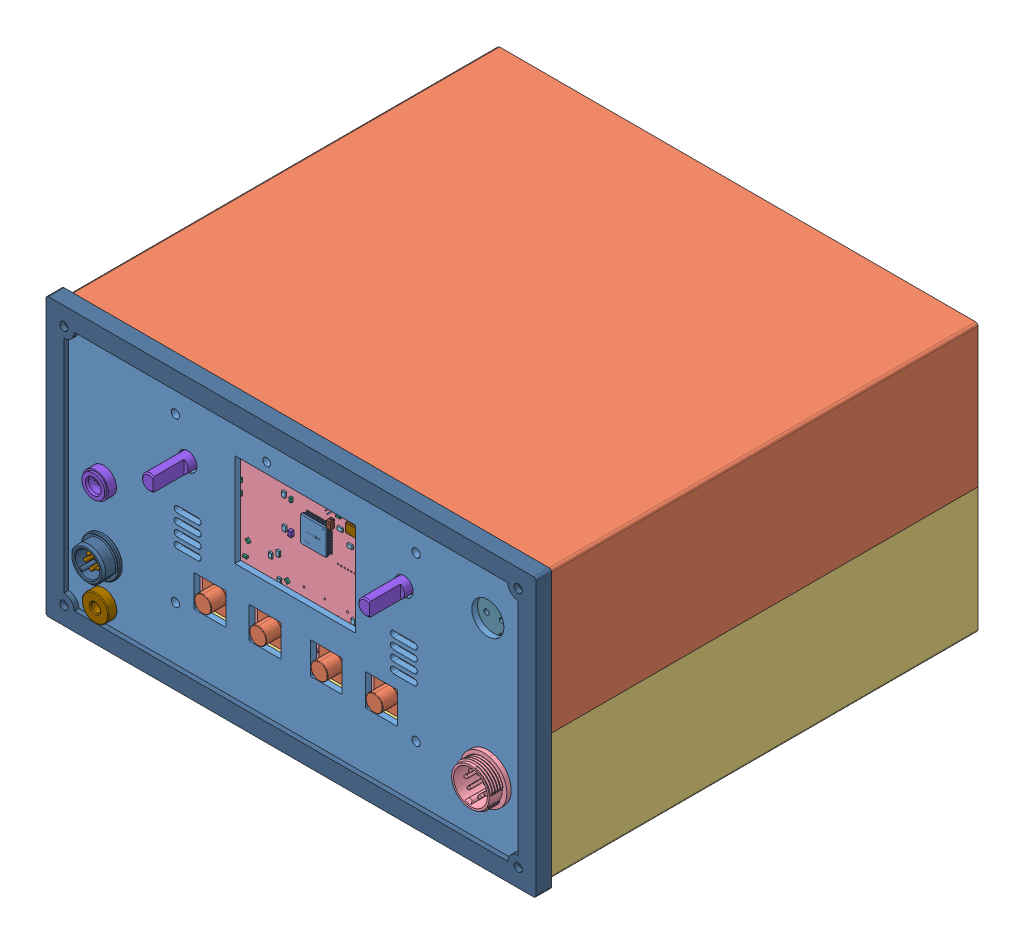
SolidWorks assembly ASM, configuration По умолчанию. Lengths in mm.
Overall size (188.8 107.81 193.5).
328 component instances, 46 part files, 35 mates.
Components (placement in the parent):
- part_1-1: part_1 [По умолчанию] at (42.0836 76.5265 112.7484) size (180 98 2.2)
- part_3-1: part_3 [По умолчанию] at (182.1946 155.2265 -55.2516) x (-1 0 0) z (0 0 1) size (185.2 54.6 170)
- part_4-1: part_4 [По умолчанию] at (182.1946 56.8265 114.7484) x (-1 0 0) z (0 0 -1) size (185.2 51.6 170)
- gx16-8-1: gx16-8 [По умолчанию] at (165.9946 82.0265 105.3984) x (0.970583 -0.240767 0) z (-0.240767 -0.970583 0) size (18 20.75 18)
- 3D_PCB_Soldering_station_p1.step-1: 3D_PCB_Soldering_station_p1.step [По умолчанию] at (42.0834 76.5267 105.1483) x (1 -0.000002 0) z (0 0 1) size (108.62 71.4 34.5)
  - DLKy-R302-R0805.step-1: DLKy-R302-R0805.step [По умолчанию] at (43.1801 57.1501 1.6) x (-1 0 0) z (0 0 1) size (2 1.3 0.61)
    - COMPOUND.step-1: COMPOUND.step [По умолчанию] at origin size (2 1.3 0.61)
  - DLKy-R303-R0805.step-1: DLKy-R303-R0805.step [По умолчанию] at (37.4651 52.7051 1.6) x (0 1 0) z (0 0 1) size (2 1.3 0.61)
    - COMPOUND.step-1: COMPOUND.step [По умолчанию] at origin size (2 1.3 0.61)
  - DLKy-R314-R0805.step-1: DLKy-R314-R0805.step [По умолчанию] at (32.3851 29.8451 1.6) x (0 1 0) z (0 0 1) size (2 1.3 0.61)
    - COMPOUND.step-1: COMPOUND.step [По умолчанию] at origin size (2 1.3 0.61)
  - DLKy-R315-R0805.step-1: DLKy-R315-R0805.step [По умолчанию] at (35.3061 31.8771 1.6) x (0 1 0) z (0 0 1) size (2 1.3 0.61)
    - COMPOUND.step-1: COMPOUND.step [По умолчанию] at origin size (2 1.3 0.61)
  - DLKy-R202-R0805.step-1: DLKy-R202-R0805.step [По умолчанию] at (62.9921 48.1331 1.6) x (-1 0 0) z (0 0 1) size (2 1.3 0.61)
    - COMPOUND.step-1: COMPOUND.step [По умолчанию] at origin size (2 1.3 0.61)
  - DLKy-R203-R0805.step-1: DLKy-R203-R0805.step [По умолчанию] at (37.7191 41.5291 1.6) x (0 1 0) z (0 0 1) size (2 1.3 0.61)
    - COMPOUND.step-1: COMPOUND.step [По умолчанию] at origin size (2 1.3 0.61)
  - DLKy-R204-R0805.step-1: DLKy-R204-R0805.step [По умолчанию] at (55.4991 61.0871 1.6) x (0 -1 0) z (0 0 1) size (2 1.3 0.61)
    - COMPOUND.step-1: COMPOUND.step [По умолчанию] at origin size (2 1.3 0.61)
  - DLKy-R501-R0805.step-1: DLKy-R501-R0805.step [По умолчанию] at (85.4712 23.622 1.6) x (0 -1 0) z (0 0 1) size (2 1.3 0.61)
    - COMPOUND.step-1: COMPOUND.step [По умолчанию] at origin size (2 1.3 0.61)
  - DLKy-R502-R0805.step-1: DLKy-R502-R0805.step [По умолчанию] at (90.5512 2.54 1.6) x (0 -1 0) z (0 0 1) size (2 1.3 0.61)
    - COMPOUND.step-1: COMPOUND.step [По умолчанию] at origin size (2 1.3 0.61)
  - DLKy-R503-R0805.step-1: DLKy-R503-R0805.step [По умолчанию] at (64.2621 23.622 1.6) x (0 -1 0) z (0 0 1) size (2 1.3 0.61)
    - COMPOUND.step-1: COMPOUND.step [По умолчанию] at origin size (2 1.3 0.61)
  - DLKy-R504-R0805.step-1: DLKy-R504-R0805.step [По умолчанию] at (69.3421 2.54 1.6) x (0 -1 0) z (0 0 1) size (2 1.3 0.61)
    - COMPOUND.step-1: COMPOUND.step [По умолчанию] at origin size (2 1.3 0.61)
  - DLKy-R505-R0805.step-1: DLKy-R505-R0805.step [По умолчанию] at (35.6871 22.987 1.6) x (0 -1 0) z (0 0 1) size (2 1.3 0.61)
    - COMPOUND.step-1: COMPOUND.step [По умолчанию] at origin size (2 1.3 0.61)
  - DLKy-R506-R0805.step-1: DLKy-R506-R0805.step [По умолчанию] at (30.4801 2.54 1.6) x (0 -1 0) z (0 0 1) size (2 1.3 0.61)
    - COMPOUND.step-1: COMPOUND.step [По умолчанию] at origin size (2 1.3 0.61)
  - DLKy-R507-R0805.step-1: DLKy-R507-R0805.step [По умолчанию] at (19.431 23.622 1.6) x (0 -1 0) z (0 0 1) size (2 1.3 0.61)
    - COMPOUND.step-1: COMPOUND.step [По умолчанию] at origin size (2 1.3 0.61)
  - DLKy-R508-R0805.step-1: DLKy-R508-R0805.step [По умолчанию] at (24.511 2.54 1.6) x (0 -1 0) z (0 0 1) size (2 1.3 0.61)
    - COMPOUND.step-1: COMPOUND.step [По умолчанию] at origin size (2 1.3 0.61)
  - DLKy-R509-R0805.step-1: DLKy-R509-R0805.step [По умолчанию] at (17.272 45.5931 1.6) x (-1 0 0) z (0 0 1) size (2 1.3 0.61)
    - COMPOUND.step-1: COMPOUND.step [По умолчанию] at origin size (2 1.3 0.61)
  - DLKy-R510-R0805.step-1: DLKy-R510-R0805.step [По умолчанию] at (17.272 48.2601 1.6) x (-1 0 0) z (0 0 1) size (2 1.3 0.61)
    - COMPOUND.step-1: COMPOUND.step [По умолчанию] at origin size (2 1.3 0.61)
  - DLKy-R514-R0805.step-1: DLKy-R514-R0805.step [По умолчанию] at (15.367 41.9101 1.6) size (2 1.3 0.61)
    - COMPOUND.step-1: COMPOUND.step [По умолчанию] at origin size (2 1.3 0.61)
  - DLKy-R515-R0805.step-1: DLKy-R515-R0805.step [По умолчанию] at (82.2962 48.1331 1.6) size (2 1.3 0.61)
    - COMPOUND.step-1: COMPOUND.step [По умолчанию] at origin size (2 1.3 0.61)
  - DLKy-R516-R0805.step-1: DLKy-R516-R0805.step [По умолчанию] at (82.2962 45.5931 1.6) size (2 1.3 0.61)
    - COMPOUND.step-1: COMPOUND.step [По умолчанию] at origin size (2 1.3 0.61)
  - DLKy-R520-R0805.step-1: DLKy-R520-R0805.step [По умолчанию] at (82.6772 37.9731 1.6) x (-1 0 0) z (0 0 1) size (2 1.3 0.61)
    - COMPOUND.step-1: COMPOUND.step [По умолчанию] at origin size (2 1.3 0.61)
  - DLKy-R522-R0805.step-1: DLKy-R522-R0805.step [По умолчанию] at (67.9451 49.1491 1.6) size (2 1.3 0.61)
    - COMPOUND.step-1: COMPOUND.step [По умолчанию] at origin size (2 1.3 0.61)
  - DLKy-R523-R0805.step-1: DLKy-R523-R0805.step [По умолчанию] at (59.1821 51.9431 1.6) x (-1 0 0) z (0 0 1) size (2 1.3 0.61)
    - COMPOUND.step-1: COMPOUND.step [По умолчанию] at origin size (2 1.3 0.61)
  - DLKy-R601-R0805.step-1: DLKy-R601-R0805.step [По умолчанию] at (11.811 23.368 1.6) x (0 -1 0) z (0 0 1) size (2 1.3 0.61)
    - COMPOUND.step-1: COMPOUND.step [По умолчанию] at origin size (2 1.3 0.61)
  - DLKy-R602-R0805.step-1: DLKy-R602-R0805.step [По умолчанию] at (14.097 23.368 1.6) x (0 1 0) z (0 0 1) size (2 1.3 0.61)
    - COMPOUND.step-1: COMPOUND.step [По умолчанию] at origin size (2 1.3 0.61)
  - DLKy-R308-R0805.step-1: DLKy-R308-R0805.step [По умолчанию] at (17.526 57.4041 0) x (-1 0 0) z (0 0 -1) size (2 1.3 0.61)
    - COMPOUND.step-1: COMPOUND.step [По умолчанию] at origin size (2 1.3 0.61)
  - DLKy-R313-R0805.step-1: DLKy-R313-R0805.step [По умолчанию] at (27.9401 65.4051 0) x (0 1 0) z (0 0 -1) size (2 1.3 0.61)
    - COMPOUND.step-1: COMPOUND.step [По умолчанию] at origin size (2 1.3 0.61)
  - DLKy-R305-R0805.step-1: DLKy-R305-R0805.step [По умолчанию] at (36.4491 50.1651 0) x (1 0 0) z (0 0 -1) size (2 1.3 0.61)
    - COMPOUND.step-1: COMPOUND.step [По умолчанию] at origin size (2 1.3 0.61)
  - DLKy-R306-R0805.step-1: DLKy-R306-R0805.step [По умолчанию] at (32.3851 50.1651 0) x (1 0 0) z (0 0 -1) size (2 1.3 0.61)
    - COMPOUND.step-1: COMPOUND.step [По умолчанию] at origin size (2 1.3 0.61)
  - DLKy-R310-R0805.step-1: DLKy-R310-R0805.step [По умолчанию] at (35.8141 62.1031 0) x (1 0 0) z (0 0 -1) size (2 1.3 0.61)
    - COMPOUND.step-1: COMPOUND.step [По умолчанию] at origin size (2 1.3 0.61)
  - DLKy-R311-R0805.step-1: DLKy-R311-R0805.step [По умолчанию] at (32.2581 63.1191 0) x (0 -1 0) z (0 0 -1) size (2 1.3 0.61)
    - COMPOUND.step-1: COMPOUND.step [По умолчанию] at origin size (2 1.3 0.61)
  - DLKy-R407-R0805.step-1: DLKy-R407-R0805.step [По умолчанию] at (20.955 32.3851 0) x (-0.707107 0.707107 0) z (0 0 -1) size (2 1.3 0.61)
    - COMPOUND.step-1: COMPOUND.step [По умолчанию] at origin size (2 1.3 0.61)
  - DLKy-R304-R0805.step-1: DLKy-R304-R0805.step [По умолчанию] at (39.6241 54.6101 0) x (1 0 0) z (0 0 -1) size (2 1.3 0.61)
    - COMPOUND.step-1: COMPOUND.step [По умолчанию] at origin size (2 1.3 0.61)
  - DLKy-R309-R0805.step-1: DLKy-R309-R0805.step [По умолчанию] at (39.6241 57.0231 0) x (1 0 0) z (0 0 -1) size (2 1.3 0.61)
    - COMPOUND.step-1: COMPOUND.step [По умолчанию] at origin size (2 1.3 0.61)
  - DLKy-R521-R0805.step-1: DLKy-R521-R0805.step [По умолчанию] at (82.6772 36.7031 0) x (-1 0 0) z (0 0 -1) size (2 1.3 0.61)
    - COMPOUND.step-1: COMPOUND.step [По умолчанию] at origin size (2 1.3 0.61)
  - DLKy-R408-R0805.step-1: DLKy-R408-R0805.step [По умолчанию] at (17.907 35.4331 0) x (-0.707107 0.707107 0) z (0 0 -1) size (2 1.3 0.61)
    - COMPOUND.step-1: COMPOUND.step [По умолчанию] at origin size (2 1.3 0.61)
  - DLKy-R409-R0805.step-1: DLKy-R409-R0805.step [По умолчанию] at (74.9301 32.0041 0) x (-1 0 0) z (0 0 -1) size (2 1.3 0.61)
    - COMPOUND.step-1: COMPOUND.step [По умолчанию] at origin size (2 1.3 0.61)
  - DLKy-R410-R0805.step-1: DLKy-R410-R0805.step [По умолчанию] at (77.4702 28.4481 0) x (0 -1 0) z (0 0 -1) size (2 1.3 0.61)
    - COMPOUND.step-1: COMPOUND.step [По умолчанию] at origin size (2 1.3 0.61)
  - DLKy-R411-R0805.step-1: DLKy-R411-R0805.step [По умолчанию] at (80.3912 28.4481 0) x (0 1 0) z (0 0 -1) size (2 1.3 0.61)
    - COMPOUND.step-1: COMPOUND.step [По умолчанию] at origin size (2 1.3 0.61)
  - DLKy-R412-R0805.step-1: DLKy-R412-R0805.step [По умолчанию] at (84.9632 28.4481 0) x (0 1 0) z (0 0 -1) size (2 1.3 0.61)
    - COMPOUND.step-1: COMPOUND.step [По умолчанию] at origin size (2 1.3 0.61)
  - DLKy-R413-R0805.step-1: DLKy-R413-R0805.step [По умолчанию] at (63.7541 32.0041 0) x (-1 0 0) z (0 0 -1) size (2 1.3 0.61)
    - COMPOUND.step-1: COMPOUND.step [По умолчанию] at origin size (2 1.3 0.61)
  - DLKy-R414-R0805.step-1: DLKy-R414-R0805.step [По умолчанию] at (66.2941 28.4481 0) x (0 -1 0) z (0 0 -1) size (2 1.3 0.61)
    - COMPOUND.step-1: COMPOUND.step [По умолчанию] at origin size (2 1.3 0.61)
  - DLKy-R415-R0805.step-1: DLKy-R415-R0805.step [По умолчанию] at (69.2151 28.4481 0) x (0 1 0) z (0 0 -1) size (2 1.3 0.61)
    - COMPOUND.step-1: COMPOUND.step [По умолчанию] at origin size (2 1.3 0.61)
  - DLKy-R416-R0805.step-1: DLKy-R416-R0805.step [По умолчанию] at (73.7871 28.4481 0) x (0 1 0) z (0 0 -1) size (2 1.3 0.61)
    - COMPOUND.step-1: COMPOUND.step [По умолчанию] at origin size (2 1.3 0.61)
  - DLKy-R603-R0805.step-1: DLKy-R603-R0805.step [По умолчанию] at (45.9741 58.2931 0) x (0 1 0) z (0 0 -1) size (2 1.3 0.61)
    - COMPOUND.step-1: COMPOUND.step [По умолчанию] at origin size (2 1.3 0.61)
  - DLKy-R604-R0805.step-1: DLKy-R604-R0805.step [По умолчанию] at (46.9901 61.8491 0) x (1 0 0) z (0 0 -1) size (2 1.3 0.61)
    - COMPOUND.step-1: COMPOUND.step [По умолчанию] at origin size (2 1.3 0.61)
  - DLKy-L201-R0805.step-1: DLKy-L201-R0805.step [По умолчанию] at (44.0691 49.0221 0) x (0 1 0) z (0 0 -1) size (2 1.3 0.61)
    - COMPOUND.step-1: COMPOUND.step [По умолчанию] at origin size (2 1.3 0.61)
  - DLKy-R401-R0805.step-1: DLKy-R401-R0805.step [По умолчанию] at (25.9081 35.9411 0) x (0 1 0) z (0 0 -1) size (2 1.3 0.61)
    - COMPOUND.step-1: COMPOUND.step [По умолчанию] at origin size (2 1.3 0.61)
  - DLKy-R402-R0805.step-1: DLKy-R402-R0805.step [По умолчанию] at (28.7021 35.9411 0) x (0 1 0) z (0 0 -1) size (2 1.3 0.61)
    - COMPOUND.step-1: COMPOUND.step [По умолчанию] at origin size (2 1.3 0.61)
  - DLKy-R403-R0805.step-1: DLKy-R403-R0805.step [По умолчанию] at (23.749 28.8291 0) x (0 1 0) z (0 0 -1) size (2 1.3 0.61)
    - COMPOUND.step-1: COMPOUND.step [По умолчанию] at origin size (2 1.3 0.61)
  - DLKy-R404-R0805.step-1: DLKy-R404-R0805.step [По умолчанию] at (33.5281 28.8291 0) x (0 1 0) z (0 0 -1) size (2 1.3 0.61)
    - COMPOUND.step-1: COMPOUND.step [По умолчанию] at origin size (2 1.3 0.61)
  - DLKy-R405-R0805.step-1: DLKy-R405-R0805.step [По умолчанию] at (27.3051 27.8131 0) x (-1 0 0) z (0 0 -1) size (2 1.3 0.61)
    - COMPOUND.step-1: COMPOUND.step [По умолчанию] at origin size (2 1.3 0.61)
  - DLKy-R406-R0805.step-1: DLKy-R406-R0805.step [По умолчанию] at (37.0841 27.8131 0) x (-1 0 0) z (0 0 -1) size (2 1.3 0.61)
    - COMPOUND.step-1: COMPOUND.step [По умолчанию] at origin size (2 1.3 0.61)
  - DLKy-R517-R0805.step-1: DLKy-R517-R0805.step [По умолчанию] at (89.0272 49.7841 0) x (0 1 0) z (0 0 -1) size (2 1.3 0.61)
    - COMPOUND.step-1: COMPOUND.step [По умолчанию] at origin size (2 1.3 0.61)
  - DLKy-R518-R0805.step-1: DLKy-R518-R0805.step [По умолчанию] at (94.1072 49.7841 0) x (0 1 0) z (0 0 -1) size (2 1.3 0.61)
    - COMPOUND.step-1: COMPOUND.step [По умолчанию] at origin size (2 1.3 0.61)
  - DLKy-R519-R0805.step-1: DLKy-R519-R0805.step [По умолчанию] at (89.0272 56.5151 0) x (0 -1 0) z (0 0 -1) size (2 1.3 0.61)
    - COMPOUND.step-1: COMPOUND.step [По умолчанию] at origin size (2 1.3 0.61)
  - DLKy-R511-R0805.step-1: DLKy-R511-R0805.step [По умолчанию] at (5.715 49.2761 0) x (0 1 0) z (0 0 -1) size (2 1.3 0.61)
    - COMPOUND.step-1: COMPOUND.step [По умолчанию] at origin size (2 1.3 0.61)
  - DLKy-R512-R0805.step-1: DLKy-R512-R0805.step [По умолчанию] at (10.795 49.2761 0) x (0 1 0) z (0 0 -1) size (2 1.3 0.61)
    - COMPOUND.step-1: COMPOUND.step [По умолчанию] at origin size (2 1.3 0.61)
  - DLKy-R513-R0805.step-1: DLKy-R513-R0805.step [По умолчанию] at (5.715 56.2611 0) x (0 -1 0) z (0 0 -1) size (2 1.3 0.61)
    - COMPOUND.step-1: COMPOUND.step [По умолчанию] at origin size (2 1.3 0.61)
  - DLKy-R201-R0805.step-1: DLKy-R201-R0805.step [По умолчанию] at (52.9591 64.3891 0) x (1 0 0) z (0 0 -1) size (2 1.3 0.61)
    - COMPOUND.step-1: COMPOUND.step [По умолчанию] at origin size (2 1.3 0.61)
  - DLKy-R307-R0805.step-1: DLKy-R307-R0805.step [По умолчанию] at (20.066 54.7371 0) x (1 0 0) z (0 0 -1) size (2 1.3 0.61)
    - COMPOUND.step-1: COMPOUND.step [По умолчанию] at origin size (2 1.3 0.61)
  - DLKy-L101-R0805.step-1: DLKy-L101-R0805.step [По умолчанию] at (43.0531 35.3061 0) x (-1 0 0) z (0 0 -1) size (2 1.3 0.61)
    - COMPOUND.step-1: COMPOUND.step [По умолчанию] at origin size (2 1.3 0.61)
  - DLKy-L102-R0805.step-1: DLKy-L102-R0805.step [По умолчанию] at (39.4971 44.9581 0) x (1 0 0) z (0 0 -1) size (2 1.3 0.61)
    - COMPOUND.step-1: COMPOUND.step [По умолчанию] at origin size (2 1.3 0.61)
  - DLKy-R312-R0805.step-1: DLKy-R312-R0805.step [По умолчанию] at (27.9401 60.5791 0) x (0 -1 0) z (0 0 -1) size (2 1.3 0.61)
    - COMPOUND.step-1: COMPOUND.step [По умолчанию] at origin size (2 1.3 0.61)
  - DLKy-R301-R0805.step-1: DLKy-R301-R0805.step [По умолчанию] at (40.3861 61.4681 1.6) x (0 -1 0) z (0 0 1) size (2 1.3 0.61)
    - COMPOUND.step-1: COMPOUND.step [По умолчанию] at origin size (2 1.3 0.61)
  - DLKy-Q3-TO-252-3_L6.5-W5.8-P4.58-TL.step-1: DLKy-Q3-TO-252-3_L6.5-W5.8-P4.58-TL.step [По умолчанию] at (35.8141 20.955 0) x (0 -1 0) z (0 0 -1) size (9.47 6.6 2.3)
    - COMPOUND-0.step-1: COMPOUND-0.step [По умолчанию] at origin size (9.47 6.6 2.3)
  - DLKy-Q5-TO-252-3_L6.5-W5.8-P4.58-TL.step-1: DLKy-Q5-TO-252-3_L6.5-W5.8-P4.58-TL.step [По умолчанию] at (82.6772 20.955 0) x (0 -1 0) z (0 0 -1) size (9.47 6.6 2.3)
    - COMPOUND-0.step-1: COMPOUND-0.step [По умолчанию] at origin size (9.47 6.6 2.3)
  - DLKy-Q7-TO-252-3_L6.5-W5.8-P4.58-TL.step-1: DLKy-Q7-TO-252-3_L6.5-W5.8-P4.58-TL.step [По умолчанию] at (71.5011 20.955 0) x (0 -1 0) z (0 0 -1) size (9.47 6.6 2.3)
    - COMPOUND-0.step-1: COMPOUND-0.step [По умолчанию] at origin size (9.47 6.6 2.3)
  - DLKy-Q2-TO-252-3_L6.5-W5.8-P4.58-TL.step-1: DLKy-Q2-TO-252-3_L6.5-W5.8-P4.58-TL.step [По умолчанию] at (26.0351 20.955 0) x (0 -1 0) z (0 0 -1) size (9.47 6.6 2.3)
    - COMPOUND-0.step-1: COMPOUND-0.step [По умолчанию] at origin size (9.47 6.6 2.3)
  - DLKy-D305-SMA_L4.3-W2.6-LS5.2-RD.step-1: DLKy-D305-SMA_L4.3-W2.6-LS5.2-RD.step [По умолчанию] at (24.257 52.4511 0) x (0 -1 0) z (0 0 -1) size (4.7 2.6 2.1)
    - COMPOUND-1.step-1: COMPOUND-1.step [По умолчанию] at origin size (4.7 2.6 2.1)
  - DLKy-D306-SMA_L4.3-W2.6-LS5.2-RD.step-1: DLKy-D306-SMA_L4.3-W2.6-LS5.2-RD.step [По умолчанию] at (21.209 61.4681 0) x (0 -1 0) z (0 0 -1) size (4.7 2.6 2.1)
    - COMPOUND-1.step-1: COMPOUND-1.step [По умолчанию] at origin size (4.7 2.6 2.1)
  - DLKy-D307-SMA_L4.3-W2.6-LS5.2-RD.step-1: DLKy-D307-SMA_L4.3-W2.6-LS5.2-RD.step [По умолчанию] at (24.765 61.5951 0) x (0 1 0) z (0 0 -1) size (4.7 2.6 2.1)
    - COMPOUND-1.step-1: COMPOUND-1.step [По умолчанию] at origin size (4.7 2.6 2.1)
  - DLKy-D101-SMA_L4.3-W2.6-LS5.2-RD.step-1: DLKy-D101-SMA_L4.3-W2.6-LS5.2-RD.step [По умолчанию] at (41.5291 24.765 0) x (0 1 0) z (0 0 -1) size (4.7 2.6 2.1)
    - COMPOUND-1.step-1: COMPOUND-1.step [По умолчанию] at origin size (4.7 2.6 2.1)
  - DLKy-D304-SMA_L4.3-W2.6-LS5.2-RD.step-1: DLKy-D304-SMA_L4.3-W2.6-LS5.2-RD.step [По умолчанию] at (27.8131 52.4511 0) x (0 1 0) z (0 0 -1) size (4.7 2.6 2.1)
    - COMPOUND-1.step-1: COMPOUND-1.step [По умолчанию] at origin size (4.7 2.6 2.1)
  - DLKy-EN2-SW-TH_PEC11R-4XXXF-SXXXX.step-1: DLKy-EN2-SW-TH_PEC11R-4XXXF-SXXXX.step [По умолчанию] at (91.5672 52.9591 1.6) size (13.6 14.6 31.2)
    - COMPOUND-2.step-1: COMPOUND-2.step [По умолчанию] at origin size (13.6 14.6 31.2)
  - DLKy-EN1-SW-TH_PEC11R-4XXXF-SXXXX.step-1: DLKy-EN1-SW-TH_PEC11R-4XXXF-SXXXX.step [По умолчанию] at (8.255 52.9591 1.6) size (13.6 14.6 31.2)
    - COMPOUND-2.step-1: COMPOUND-2.step [По умолчанию] at origin size (13.6 14.6 31.2)
  - DLKy-U6-SOP-8_L4.9-W3.9-P1.27-LS6.0-BL-1.step-1: DLKy-U6-SOP-8_L4.9-W3.9-P1.27-LS6.0-BL-1.step [По умолчанию] at (64.7693 54.7362 1.6) x (-1 0 0) z (0 0 1) size (4.9 6 1.5)
    - COMPOUND-3.step-1: COMPOUND-3.step [По умолчанию] at origin size (4.9 6 1.5)
  - DLKy-C107-CASE-A_3216.step-1: DLKy-C107-CASE-A_3216.step [По умолчанию] at (34.4171 42.7991 0) x (-1 0 0) z (0 0 -1) size (3.2 1.6 1.7)
    - COMPOUND-4.step-1: COMPOUND-4.step [По умолчанию] at origin size (3.2 1.6 1.7)
  - DLKy-C211-CASE-A_3216.step-1: DLKy-C211-CASE-A_3216.step [По умолчанию] at (56.0071 52.3241 1.6) x (0 -1 0) z (0 0 1) size (3.2 1.6 1.7)
    - COMPOUND-5.step-1: COMPOUND-5.step [По умолчанию] at origin size (3.2 1.6 1.7)
  - DLKy-U1-TO-252-2_L6.6-W6.1-P4.57-LS9.9-BR-CW.step-1: DLKy-U1-TO-252-2_L6.6-W6.1-P4.57-LS9.9-BR-CW.step [По умолчанию] at (50.9271 32.6391 0) x (-1 0 0) z (0 0 -1) size (9.92 6.6 2.3)
    - COMPOUND-6.step-1: COMPOUND-6.step [По умолчанию] at origin size (9.92 6.6 2.3)
  - DLKy-POWER-CONN-TH_P5.08_KF2EDGRC-5.08-2P.step-1: DLKy-POWER-CONN-TH_P5.08_KF2EDGRC-5.08-2P.step [По умолчанию] at (49.9111 9.271 0) x (-1 0 0) z (0 0 -1) size (11.61 11.74 11.84)
    - COMPOUND-7.step-1: COMPOUND-7.step [По умолчанию] at origin size (11.61 11.74 11.84)
  - DLKy-Q6-SOT-23-3_L2.9-W1.3-P1.90-LS2.4-BR.step-1: DLKy-Q6-SOT-23-3_L2.9-W1.3-P1.90-LS2.4-BR.step [По умолчанию] at (68.1991 32.5121 0) x (-1 0 0) z (0 0 -1) size (2.5 2.89 1.05)
    - COMPOUND-8.step-1: COMPOUND-8.step [По умолчанию] at origin size (2.5 2.89 1.05)
  - DLKy-Q1-SOT-23-3_L2.9-W1.3-P1.90-LS2.4-BR.step-1: DLKy-Q1-SOT-23-3_L2.9-W1.3-P1.90-LS2.4-BR.step [По умолчанию] at (27.3051 31.2421 0) x (0 1 0) z (0 0 -1) size (2.5 2.89 1.05)
    - COMPOUND-8.step-1: COMPOUND-8.step [По умолчанию] at origin size (2.5 2.89 1.05)
  - DLKy-Q4-SOT-23-3_L2.9-W1.3-P1.90-LS2.4-BR.step-1: DLKy-Q4-SOT-23-3_L2.9-W1.3-P1.90-LS2.4-BR.step [По умолчанию] at (79.3752 32.5121 0) x (-1 0 0) z (0 0 -1) size (2.5 2.89 1.05)
    - COMPOUND-8.step-1: COMPOUND-8.step [По умолчанию] at origin size (2.5 2.89 1.05)
  - DLKy-FAN-CONN-TH_P5.00_KF301-5.0-2P.step-1: DLKy-FAN-CONN-TH_P5.00_KF301-5.0-2P.step [По умолчанию] at (72.3901 5.969 0) x (-1 0 0) z (0 0 -1) size (10.4 7.7 14.2)
    - COMPOUND-9.step-1: COMPOUND-9.step [По умолчанию] at origin size (10.4 7.7 14.2)
  - DLKy-U4-SOIC-8_L4.9-W3.9-P1.27-LS6.0-BL.step-1: DLKy-U4-SOIC-8_L4.9-W3.9-P1.27-LS6.0-BL.step [По умолчанию] at (34.6711 56.0071 0) x (-1 0 0) z (0 0 -1) size (4.81 6 1.72)
    - COMPOUND-10.step-1: COMPOUND-10.step [По умолчанию] at origin size (4.81 6 1.72)
  - DLKy-U5-SOIC-8_L4.9-W3.9-P1.27-LS6.0-BL.step-1: DLKy-U5-SOIC-8_L4.9-W3.9-P1.27-LS6.0-BL.step [По умолчанию] at (15.621 26.1621 0) x (-0.707107 0.707107 0) z (0 0 -1) size (4.81 6 1.72)
    - COMPOUND-10.step-1: COMPOUND-10.step [По умолчанию] at origin size (4.81 6 1.72)
  - DLKy-D303-SOD-323_L1.7-W1.3-LS2.5-RD.step-1: DLKy-D303-SOD-323_L1.7-W1.3-LS2.5-RD.step [По умолчанию] at (11.176 31.1151 0) x (0.707107 -0.707107 0) z (0 0 -1) size (2.5 1.25 0.95)
    - COMPOUND-11.step-1: COMPOUND-11.step [По умолчанию] at origin size (2.5 1.25 0.95)
  - DLKy-D302-SOD-323_L1.7-W1.3-LS2.5-RD.step-1: DLKy-D302-SOD-323_L1.7-W1.3-LS2.5-RD.step [По умолчанию] at (89.1542 31.3691 0) x (0 1 0) z (0 0 -1) size (2.5 1.25 0.95)
    - COMPOUND-11.step-1: COMPOUND-11.step [По умолчанию] at origin size (2.5 1.25 0.95)
  - DLKy-D301-SOD-323_L1.7-W1.3-LS2.5-RD.step-1: DLKy-D301-SOD-323_L1.7-W1.3-LS2.5-RD.step [По умолчанию] at (45.9741 61.2141 1.6) x (0 -1 0) z (0 0 1) size (2.5 1.25 0.95)
    - COMPOUND-12.step-1: COMPOUND-12.step [По умолчанию] at origin size (2.5 1.25 0.95)
  - DLKy-U3-LQFP-64_L10.0-W10.0-P0.50-LS12.0-BL.step-1: DLKy-U3-LQFP-64_L10.0-W10.0-P0.50-LS12.0-BL.step [По умолчанию] at (49.9111 45.5931 1.6) x (-1 0 0) z (0 0 1) size (12 12 1.45)
    - COMPOUND-13.step-1: COMPOUND-13.step [По умолчанию] at origin size (12 12 1.45)
  - DLKy-K_2-KEY-SMD_4P-L12.0-W12.0-P5.00-LS15.2-1.step-1: DLKy-K_2-KEY-SMD_4P-L12.0-W12.0-P5.00-LS15.2-1.step [По умолчанию] at (61.7221 11.049 1.6) x (0 -1 0) z (0 0 1) size (15.2 12 11.01)
    - COMPOUND-14.step-1: COMPOUND-14.step [По умолчанию] at origin size (15.2 12 11.01)
  - DLKy-K_3-KEY-SMD_4P-L12.0-W12.0-P5.00-LS15.2-1.step-1: DLKy-K_3-KEY-SMD_4P-L12.0-W12.0-P5.00-LS15.2-1.step [По умолчанию] at (38.1001 11.049 1.6) x (0 1 0) z (0 0 1) size (15.2 12 11.01)
    - COMPOUND-14.step-1: COMPOUND-14.step [По умолчанию] at origin size (15.2 12 11.01)
  - DLKy-K_4-KEY-SMD_4P-L12.0-W12.0-P5.00-LS15.2-1.step-1: DLKy-K_4-KEY-SMD_4P-L12.0-W12.0-P5.00-LS15.2-1.step [По умолчанию] at (16.891 11.049 1.6) x (0 -1 0) z (0 0 1) size (15.2 12 11.01)
    - COMPOUND-14.step-1: COMPOUND-14.step [По умолчанию] at origin size (15.2 12 11.01)
  - DLKy-K_1-KEY-SMD_4P-L12.0-W12.0-P5.00-LS15.2-1.step-1: DLKy-K_1-KEY-SMD_4P-L12.0-W12.0-P5.00-LS15.2-1.step [По умолчанию] at (82.9312 11.049 1.6) x (0 -1 0) z (0 0 1) size (15.2 12 11.01)
    - COMPOUND-14.step-1: COMPOUND-14.step [По умолчанию] at origin size (15.2 12 11.01)
  - DLKy-IRON-CONN-TH_5P-P5.08_KF2EDGRC-5.08-5P.step-1: DLKy-IRON-CONN-TH_5P-P5.08_KF2EDGRC-5.08-5P.step [По умолчанию] at (6.477 25.0191 0) x (0 1 0) z (0 0 -1) size (27 12.2 12.5)
    - COMPOUND-15.step-1: COMPOUND-15.step [По умолчанию] at origin size (27 12.2 12.5)
  - DLKy-HOTAIR-CONN-TH_5P-P5.08_KF2EDGRC-5.08-5P.step-1: DLKy-HOTAIR-CONN-TH_5P-P5.08_KF2EDGRC-5.08-5P.step [По умолчанию] at (93.3452 25.0191 0) x (0 -1 0) z (0 0 -1) size (27 12.2 12.5)
    - COMPOUND-15.step-1: COMPOUND-15.step [По умолчанию] at origin size (27 12.2 12.5)
  - DLKy-Board.step-1: DLKy-Board.step [По умолчанию] at origin size (99.8 69.95 1.6)
  - DLKy-XTAL2-CRYSTAL-TH_BD3.0-P1.10-D0.4.step-1: DLKy-XTAL2-CRYSTAL-TH_BD3.0-P1.10-D0.4.step [По умолчанию] at (55.3721 56.3881 0) x (0.707107 -0.707107 0) z (0 0 -1) size (3 3.01 11.5)
  - DLKy-C301-C0603.step-1: DLKy-C301-C0603.step [По умолчанию] at (58.6741 60.0711 1.6) size (1.6 0.8 0.8)
  - DLKy-C301-C0603.step-2: DLKy-C301-C0603.step [По умолчанию] at (58.6741 61.9761 1.6) size (1.6 0.8 0.8)
  - DLKy-C301-C0603.step-3: DLKy-C301-C0603.step [По умолчанию] at (58.6741 56.0071 1.6) size (1.6 0.8 0.8)
  - DLKy-C301-C0603.step-4: DLKy-C301-C0603.step [По умолчанию] at (58.6741 57.9121 1.6) size (1.6 0.8 0.8)
  - DLKy-C301-C0603.step-5: DLKy-C301-C0603.step [По умолчанию] at (40.2591 52.3241 1.6) x (0 1 0) z (0 0 1) size (1.6 0.8 0.8)
  - DLKy-C301-C0603.step-6: DLKy-C301-C0603.step [По умолчанию] at (23.749 30.3531 1.6) x (-0.707107 0.707107 0) z (0 0 1) size (1.6 0.8 0.8)
  - DLKy-C301-C0603.step-7: DLKy-C301-C0603.step [По умолчанию] at (82.1692 24.638 1.6) size (1.6 0.8 0.8)
  - DLKy-C301-C0603.step-8: DLKy-C301-C0603.step [По умолчанию] at (66.4211 25.2731 1.6) x (0 -1 0) z (0 0 1) size (1.6 0.8 0.8)
  - DLKy-C301-C0603.step-9: DLKy-C301-C0603.step [По умолчанию] at (38.8621 24.511 1.6) x (-0.707107 0.707107 0) z (0 0 1) size (1.6 0.8 0.8)
  - DLKy-C301-C0603.step-10: DLKy-C301-C0603.step [По умолчанию] at (22.733 24.638 1.6) x (-1 0 0) z (0 0 1) size (1.6 0.8 0.8)
  - DLKy-C301-C0603.step-11: DLKy-C301-C0603.step [По умолчанию] at (20.828 44.7041 1.6) x (0 1 0) z (0 0 1) size (1.6 0.8 0.8)
  - DLKy-C301-C0603.step-12: DLKy-C301-C0603.step [По умолчанию] at (20.828 49.1491 1.6) x (0 -1 0) z (0 0 1) size (1.6 0.8 0.8)
  - DLKy-C301-C0603.step-13: DLKy-C301-C0603.step [По умолчанию] at (18.923 41.1481 1.6) x (0 1 0) z (0 0 1) size (1.6 0.8 0.8)
  - DLKy-C301-C0603.step-14: DLKy-C301-C0603.step [По умолчанию] at (79.1212 48.8951 1.6) x (0 -1 0) z (0 0 1) size (1.6 0.8 0.8)
  - DLKy-C301-C0603.step-15: DLKy-C301-C0603.step [По умолчанию] at (79.1212 44.8311 1.6) x (0 1 0) z (0 0 1) size (1.6 0.8 0.8)
  - DLKy-C301-C0603.step-16: DLKy-C301-C0603.step [По умолчанию] at (79.2482 38.7351 1.6) x (0 -1 0) z (0 0 1) size (1.6 0.8 0.8)
  - DLKy-C301-C0603.step-17: DLKy-C301-C0603.step [По умолчанию] at (74.0411 52.9591 1.6) x (0 -1 0) z (0 0 1) size (1.6 0.8 0.8)
  - DLKy-C301-C0603.step-18: DLKy-C301-C0603.step [По умолчанию] at (69.0881 52.8321 1.6) x (0 -1 0) z (0 0 1) size (1.6 0.8 0.8)
  - DLKy-C301-C0603.step-19: DLKy-C301-C0603.step [По умолчанию] at (9.398 23.749 1.6) x (0 1 0) z (0 0 1) size (1.6 0.8 0.8)
  - DLKy-C301-C0603.step-20: DLKy-C301-C0603.step [По умолчанию] at (50.1651 52.4511 0) x (0 -1 0) z (0 0 -1) size (1.6 0.8 0.8)
  - DLKy-C301-C0603.step-21: DLKy-C301-C0603.step [По умолчанию] at (48.5141 57.9121 0) x (0 -1 0) z (0 0 -1) size (1.6 0.8 0.8)
  - DLKy-C301-C0603.step-22: DLKy-C301-C0603.step [По умолчанию] at (49.6571 48.3871 0) x (0 -1 0) z (0 0 -1) size (1.6 0.8 0.8)
  - DLKy-C301-C0603.step-23: DLKy-C301-C0603.step [По умолчанию] at (46.9901 45.4661 0) x (1 0 0) z (0 0 -1) size (1.6 0.8 0.8)
  - DLKy-C301-C0603.step-24: DLKy-C301-C0603.step [По умолчанию] at (46.9901 43.3071 0) x (1 0 0) z (0 0 -1) size (1.6 0.8 0.8)
  - DLKy-C301-C0603.step-25: DLKy-C301-C0603.step [По умолчанию] at (52.7051 45.4661 0) x (-1 0 0) z (0 0 -1) size (1.6 0.8 0.8)
  - DLKy-C301-C0603.step-26: DLKy-C301-C0603.step [По умолчанию] at (52.7051 43.3071 0) x (-1 0 0) z (0 0 -1) size (1.6 0.8 0.8)
  - DLKy-C301-C0603.step-27: DLKy-C301-C0603.step [По умолчанию] at (39.8781 52.0701 0) x (-1 0 0) z (0 0 -1) size (1.6 0.8 0.8)
  - DLKy-C301-C0603.step-28: DLKy-C301-C0603.step [По умолчанию] at (39.8781 59.6901 0) x (-1 0 0) z (0 0 -1) size (1.6 0.8 0.8)
  - DLKy-C301-C0603.step-29: DLKy-C301-C0603.step [По умолчанию] at (51.8161 62.2301 0) x (-1 0 0) z (0 0 -1) size (1.6 0.8 0.8)
  - DLKy-C301-C0603.step-30: DLKy-C301-C0603.step [По умолчанию] at (21.082 51.6891 0) x (0 -1 0) z (0 0 -1) size (1.6 0.8 0.8)
  - DLKy-C301-C0603.step-31: DLKy-C301-C0603.step [По умолчанию] at (30.0991 58.4201 0) x (0 -1 0) z (0 0 -1) size (1.6 0.8 0.8)
  - DLKy-C301-C0603.step-32: DLKy-C301-C0603.step [По умолчанию] at (18.034 31.3691 0) x (0.707107 -0.707107 0) z (0 0 -1) size (1.6 0.8 0.8)
  - DLKy-C301-C0603.step-33: DLKy-C301-C0603.step [По умолчанию] at (44.0691 38.4811 0) x (0 -1 0) z (0 0 -1) size (1.6 0.8 0.8)
  - DLKy-C301-C0603.step-34: DLKy-C301-C0603.step [По умолчанию] at (42.0371 38.4811 0) x (0 -1 0) z (0 0 -1) size (1.6 0.8 0.8)
  - DLKy-C301-C0603.step-35: DLKy-C301-C0603.step [По умолчанию] at (38.6081 32.2581 0) x (0 1 0) z (0 0 -1) size (1.6 0.8 0.8)
  - DLKy-C301-C0603.step-36: DLKy-C301-C0603.step [По умолчанию] at (34.9251 44.9581 0) x (1 0 0) z (0 0 -1) size (1.6 0.8 0.8)
  - DLKy-C301-C0603.step-37: DLKy-C301-C0603.step [По умолчанию] at (42.7991 44.1961 0) x (0 1 0) z (0 0 -1) size (1.6 0.8 0.8)
  - DLKy-C301-C0603.step-38: DLKy-C301-C0603.step [По умолчанию] at (41.0211 49.9111 0) x (1 0 0) z (0 0 -1) size (1.6 0.8 0.8)
  - DLKy-C301-C0603.step-39: DLKy-C301-C0603.step [По умолчанию] at (45.2121 51.9431 0) x (-1 0 0) z (0 0 -1) size (1.6 0.8 0.8)
  - DLKy-C301-C0603.step-40: DLKy-C301-C0603.step [По умолчанию] at (43.9421 61.4681 1.6) x (0 -1 0) z (0 0 1) size (1.6 0.8 0.8)
  - DLKy-CONTROL-CONN-TH_XH2.54-4AW.step-1: DLKy-CONTROL-CONN-TH_XH2.54-4AW.step [По умолчанию] at (70.2311 62.6111 0) x (-1 0 0) z (0 0 -1) size (12.62 7.7 9.1)
  - DLKy-C511-C0805.step-1: DLKy-C511-C0805.step [По умолчанию] at (40.5131 41.4021 1.6) x (0 1 0) z (0 0 1) size (2 1.3 1.3)
  - DLKy-C511-C0805.step-2: DLKy-C511-C0805.step [По умолчанию] at (48.5141 27.9401 0) x (-1 0 0) z (0 0 -1) size (2 1.3 1.3)
  - DLKy-C511-C0805.step-3: DLKy-C511-C0805.step [По умолчанию] at (52.5781 18.288 0) x (0 1 0) z (0 0 -1) size (2 1.3 1.3)
  - DLKy-C511-C0805.step-4: DLKy-C511-C0805.step [По умолчанию] at (45.7201 53.9751 0) x (-1 0 0) z (0 0 -1) size (2 1.3 1.3)
  - DLKy-C511-C0805.step-5: DLKy-C511-C0805.step [По умолчанию] at (71.6281 53.3401 1.6) x (0 -1 0) z (0 0 1) size (2 1.3 1.3)
- GX12-5 Jack.step-1: GX12-5 Jack.step [По умолчанию] at (17.9946 82.0265 114.9484) x (0 0 -1) z (0.754496 -0.656305 0) size (20.41 17.32 15)
  - Array.step-1: Array.step [По умолчанию] at origin size (18.75 6.92 7.28)
    - Body003.step-1: Body003.step [По умолчанию] at (0 2.5 0) size (18.75 2 2)
    - Body003.step-2: Body003.step [По умолчанию] at (0 0.7725 2.3776) x (1 0 0) z (0 -0.951057 0.309017) size (18.75 2 2)
    - Body003.step-3: Body003.step [По умолчанию] at (0 -2.0225 1.4695) x (1 0 0) z (0 -0.587785 -0.809017) size (18.75 2 2)
    - Body003.step-4: Body003.step [По умолчанию] at (0 -2.0225 -1.4695) x (1 0 0) z (0 0.587785 -0.809017) size (18.75 2 2)
    - Body003.step-5: Body003.step [По умолчанию] at (0 0.7725 -2.3776) x (1 0 0) z (0 0.951057 0.309017) size (18.75 2 2)
  - Body.step-1: Body.step [По умолчанию] at origin size (15.76 15 15)
  - Body001.step-1: Body001.step [По умолчанию] at (3 0 0) size (2.5 17.32 15)
  - Body002.step-1: Body002.step [По умолчанию] at origin size (5.15 9.54 9.6)
  - Body004.step-1: Body004.step [По умолчанию] at origin size (1 13 13)
- 3D_PCB_Soldering_station_p2.step-1: 3D_PCB_Soldering_station_p2.step [По умолчанию] at (42.0837 76.5266 77.5483) x (1 -0.000001 0) z (0 0 1) size (99.8 69.95 31.2)
  - CG8F-D2-SMA_L4.3-W2.6-LS5.2-RD.step-1: CG8F-D2-SMA_L4.3-W2.6-LS5.2-RD.step [По умолчанию] at (41.0211 35.3061 0) x (0 1 0) z (0 0 -1) size (2 1.3 0.61)
    - COMPOUND.step-1: COMPOUND.step [По умолчанию] at origin size (2 1.3 0.61)
  - CG8F-D3-SMA_L4.3-W2.6-LS5.2-RD.step-1: CG8F-D3-SMA_L4.3-W2.6-LS5.2-RD.step [По умолчанию] at (41.0211 18.923 0) x (0 1 0) z (0 0 -1) size (2 1.3 0.61)
    - COMPOUND.step-1: COMPOUND.step [По умолчанию] at origin size (2 1.3 0.61)
  - CG8F-D1-SMA_L4.3-W2.6-LS5.2-RD.step-1: CG8F-D1-SMA_L4.3-W2.6-LS5.2-RD.step [По умолчанию] at (41.0211 51.6891 0) x (0 1 0) z (0 0 -1) size (2 1.3 0.61)
    - COMPOUND.step-1: COMPOUND.step [По умолчанию] at origin size (2 1.3 0.61)
  - CG8F-POWER_2-CONN-TH_P5.08_KF2EDGRC-5.08-2P.step-1: CG8F-POWER_2-CONN-TH_P5.08_KF2EDGRC-5.08-2P.step [По умолчанию] at (93.3452 55.1181 0) x (0 -1 0) z (0 0 -1) size (9.47 6.6 2.3)
    - COMPOUND-0.step-1: COMPOUND-0.step [По умолчанию] at origin size (9.47 6.6 2.3)
  - CG8F-POWER_1-CONN-TH_P5.08_KF2EDGRC-5.08-2P.step-1: CG8F-POWER_1-CONN-TH_P5.08_KF2EDGRC-5.08-2P.step [По умолчанию] at (93.3452 38.9891 0) x (0 -1 0) z (0 0 -1) size (9.47 6.6 2.3)
    - COMPOUND-0.step-1: COMPOUND-0.step [По умолчанию] at origin size (9.47 6.6 2.3)
  - CG8F-Q3-SOT-23-3_L2.9-W1.3-P1.90-LS2.4-BR.step-1: CG8F-Q3-SOT-23-3_L2.9-W1.3-P1.90-LS2.4-BR.step [По умолчанию] at (64.0081 34.5441 0) x (0.707107 0.707107 0) z (0 0 -1) size (4.7 2.6 2.1)
    - COMPOUND-1.step-1: COMPOUND-1.step [По умолчанию] at origin size (4.7 2.6 2.1)
  - CG8F-Q2-SOT-23-3_L2.9-W1.3-P1.90-LS2.4-BR.step-1: CG8F-Q2-SOT-23-3_L2.9-W1.3-P1.90-LS2.4-BR.step [По умолчанию] at (49.1491 41.1481 0) x (0.707107 -0.707107 0) z (0 0 -1) size (4.7 2.6 2.1)
    - COMPOUND-1.step-1: COMPOUND-1.step [По умолчанию] at origin size (4.7 2.6 2.1)
  - CG8F-R102-R0805.step-1: CG8F-R102-R0805.step [По умолчанию] at (75.5652 33.0201 0) x (0.707107 -0.707107 0) z (0 0 -1) size (13.6 14.6 31.2)
    - COMPOUND-2.step-1: COMPOUND-2.step [По умолчанию] at origin size (13.6 14.6 31.2)
  - CG8F-R106-R0805.step-1: CG8F-R106-R0805.step [По умолчанию] at (59.5631 58.0391 0) x (1 0 0) z (0 0 -1) size (13.6 14.6 31.2)
    - COMPOUND-2.step-1: COMPOUND-2.step [По умолчанию] at origin size (13.6 14.6 31.2)
  - CG8F-R107-R0805.step-1: CG8F-R107-R0805.step [По умолчанию] at (55.7531 57.0231 0) x (0 1 0) z (0 0 -1) size (13.6 14.6 31.2)
    - COMPOUND-2.step-1: COMPOUND-2.step [По умолчанию] at origin size (13.6 14.6 31.2)
  - CG8F-R108-R0805.step-1: CG8F-R108-R0805.step [По умолчанию] at (54.7371 40.1321 0) x (1 0 0) z (0 0 -1) size (13.6 14.6 31.2)
    - COMPOUND-2.step-1: COMPOUND-2.step [По умолчанию] at origin size (13.6 14.6 31.2)
  - CG8F-R109-R0805.step-1: CG8F-R109-R0805.step [По умолчанию] at (54.7371 37.5921 0) x (-1 0 0) z (0 0 -1) size (13.6 14.6 31.2)
    - COMPOUND-2.step-1: COMPOUND-2.step [По умолчанию] at origin size (13.6 14.6 31.2)
  - CG8F-R110-R0805.step-1: CG8F-R110-R0805.step [По умолчанию] at (72.5171 57.9121 0) x (1 0 0) z (0 0 -1) size (13.6 14.6 31.2)
    - COMPOUND-2.step-1: COMPOUND-2.step [По умолчанию] at origin size (13.6 14.6 31.2)
  - CG8F-R111-R0805.step-1: CG8F-R111-R0805.step [По умолчанию] at (68.7071 56.8961 0) x (0 1 0) z (0 0 -1) size (13.6 14.6 31.2)
    - COMPOUND-2.step-1: COMPOUND-2.step [По умолчанию] at origin size (13.6 14.6 31.2)
  - CG8F-R112-R0805.step-1: CG8F-R112-R0805.step [По умолчанию] at (67.6911 40.0051 0) x (1 0 0) z (0 0 -1) size (13.6 14.6 31.2)
    - COMPOUND-2.step-1: COMPOUND-2.step [По умолчанию] at origin size (13.6 14.6 31.2)
  - CG8F-R113-R0805.step-1: CG8F-R113-R0805.step [По умолчанию] at (67.6911 37.4651 0) x (-1 0 0) z (0 0 -1) size (13.6 14.6 31.2)
    - COMPOUND-2.step-1: COMPOUND-2.step [По умолчанию] at origin size (13.6 14.6 31.2)
  - CG8F-R101-R0805.step-1: CG8F-R101-R0805.step [По умолчанию] at (76.4542 37.4651 0) x (0 -1 0) z (0 0 -1) size (13.6 14.6 31.2)
    - COMPOUND-2.step-1: COMPOUND-2.step [По умолчанию] at origin size (13.6 14.6 31.2)
  - CG8F-Q1-TO-220-3_L10.0-W4.5-P2.54-L.step-1: CG8F-Q1-TO-220-3_L10.0-W4.5-P2.54-L.step [По умолчанию] at (77.8512 8.128 0) x (1 0 0) z (0 0 -1) size (4.9 6 1.5)
    - COMPOUND-3.step-1: COMPOUND-3.step [По умолчанию] at origin size (4.9 6 1.5)
  - CG8F-INPUT-CONN-TH_P5.00_KF301-5.0-2P.step-1: CG8F-INPUT-CONN-TH_P5.00_KF301-5.0-2P.step [По умолчанию] at (3.683 44.1961 0) x (0 1 0) z (0 0 -1) size (3.2 1.6 1.7)
    - COMPOUND-4.step-1: COMPOUND-4.step [По умолчанию] at origin size (3.2 1.6 1.7)
  - CG8F-POWER_SUPPLY-CONN-TH_P5.00_KF301-5.0-2P.step-1: CG8F-POWER_SUPPLY-CONN-TH_P5.00_KF301-5.0-2P.step [По умолчанию] at (3.683 32.5121 0) x (0 1 0) z (0 0 -1) size (3.2 1.6 1.7)
    - COMPOUND-4.step-1: COMPOUND-4.step [По умолчанию] at origin size (3.2 1.6 1.7)
  - CG8F-BUTTON-CONN-TH_P5.00_KF301-5.0-2P.step-1: CG8F-BUTTON-CONN-TH_P5.00_KF301-5.0-2P.step [По умолчанию] at (3.683 55.8801 0) x (0 1 0) z (0 0 -1) size (3.2 1.6 1.7)
    - COMPOUND-4.step-1: COMPOUND-4.step [По умолчанию] at origin size (3.2 1.6 1.7)
  - CG8F-HOTAIR-CONN-TH_3P-P5.08_KF2EDGRC-5.08-3P.step-1: CG8F-HOTAIR-CONN-TH_3P-P5.08_KF2EDGRC-5.08-3P.step [По умолчанию] at (93.3452 19.431 0) x (0 -1 0) z (0 0 -1) size (3.2 1.6 1.7)
    - COMPOUND-5.step-1: COMPOUND-5.step [По умолчанию] at origin size (3.2 1.6 1.7)
  - CG8F-U1-SOP-6_L8.5-W6.4-P2.54-LS9.2-BL.step-1: CG8F-U1-SOP-6_L8.5-W6.4-P2.54-LS9.2-BL.step [По умолчанию] at (70.8661 26.2891 0) x (0.707107 -0.707107 0) z (0 0 -1) size (9.92 6.6 2.3)
    - COMPOUND-6.step-1: COMPOUND-6.step [По умолчанию] at origin size (9.92 6.6 2.3)
  - CG8F-U3-SMD-4_L4.6-W6.5-P2.54-LS10.2-BL.step-1: CG8F-U3-SMD-4_L4.6-W6.5-P2.54-LS10.2-BL.step [По умолчанию] at (69.9771 48.0061 0) x (1 0 0) z (0 0 -1) size (11.61 11.74 11.84)
    - COMPOUND-7.step-1: COMPOUND-7.step [По умолчанию] at origin size (11.61 11.74 11.84)
  - CG8F-U2-SMD-4_L4.6-W6.5-P2.54-LS10.2-BL.step-1: CG8F-U2-SMD-4_L4.6-W6.5-P2.54-LS10.2-BL.step [По умолчанию] at (57.0231 48.1331 0) x (1 0 0) z (0 0 -1) size (11.61 11.74 11.84)
    - COMPOUND-7.step-1: COMPOUND-7.step [По умолчанию] at origin size (11.61 11.74 11.84)
  - CG8F-Board.step-1: CG8F-Board.step [По умолчанию] at origin size (99.8 69.95 1.6)
  - CG8F-F1-F1206.step-1: CG8F-F1-F1206.step [По умолчанию] at (87.8842 35.0521 0) x (0 -1 0) z (0 0 -1) size (3.2 1.7 0.6)
  - CG8F-K1-RELAY-TH_SRD-DCXXV-SL-C.step-1: CG8F-K1-RELAY-TH_SRD-DCXXV-SL-C.step [По умолчанию] at (28.4481 39.2431 0) x (-1 0 0) z (0 0 -1) size (19.2 15.6 19.8)
  - CG8F-K1-RELAY-TH_SRD-DCXXV-SL-C.step-2: CG8F-K1-RELAY-TH_SRD-DCXXV-SL-C.step [По умолчанию] at (28.4481 22.86 0) x (-1 0 0) z (0 0 -1) size (19.2 15.6 19.8)
  - CG8F-K1-RELAY-TH_SRD-DCXXV-SL-C.step-3: CG8F-K1-RELAY-TH_SRD-DCXXV-SL-C.step [По умолчанию] at (28.4481 55.6261 0) x (-1 0 0) z (0 0 -1) size (19.2 15.6 19.8)
  - CG8F-C101-CAP-TH_L16.0-W5.5-P15.00-D1.2.step-1: CG8F-C101-CAP-TH_L16.0-W5.5-P15.00-D1.2.step [По умолчанию] at (58.2931 10.287 0) x (-1 0 0) z (0 0 -1) size (16 5.5 20.01)
  - CG8F-CONTROL-CONN-TH_XH2.54-4AW.step-1: CG8F-CONTROL-CONN-TH_XH2.54-4AW.step [По умолчанию] at (70.231 62.611 0) x (-1 0 0) z (0 0 -1) size (12.62 7.7 9.1)
- power_supply-1: power_supply [По умолчанию] at (16.7946 56.8265 48.7484) x (1 0 0) z (0 1 0) size (150 70 45)
- part_2-1: part_2 [По умолчанию] at (1.9946 57.0265 -55.2516) size (180 98 2)
- AC-14-F18-1: AC-14-F18 [По умолчанию] at (146.9946 121.4265 -55.2516) x (1 0 0) z (0 0 -1) size (49.46 51.3 37.3)
- PC cooling fan.STEP-1: PC cooling fan.STEP [По умолчанию] at (61.7446 106.2765 -40.7516) x (0 1 0) z (1 0 0) size (107.81 25.32 107.42)
  - Assem1.STEP-1: Assem1.STEP [По умолчанию] at origin size (91.01 25.32 91.01)
    - fan body case.STEP-1: fan body case.STEP [По умолчанию] at origin size (91.01 25.32 91.01)
    - Part3^Assem1.STEP-1: Part3^Assem1.STEP [По умолчанию] at origin size (31 1.25 31)
  - Part4.STEP-1: Part4.STEP [По умолчанию] at (0 -7.65 0) x (0.68473 0 0.728797) z (-0.728797 0 0.68473) size (32 14 32)
  - fanl blade.STEP-1: fanl blade.STEP [По умолчанию] at (0 -7.65 0) x (-0.854524 0 0.519412) z (-0.519412 0 -0.854524) size (78.91 20.75 77.74)
- Jack_2.5_ST.step-1: Jack_2.5_ST.step [По умолчанию] at (17.9946 107.0265 106.8484) size (9.9 9.9 17.8)
- PJ-390A.stp-1: PJ-390A.stp [По умолчанию] at (17.9946 66.0265 114.9484) size (10.2 10.97 20.5)
- frame-1: frame [По умолчанию] at (-2.4054 159.4265 116.7484) x (1 0 0) z (0 0 -1) size (188.8 106.8 6)
Mates (geometry in assembly coordinates):
- Совпадение1: coincident anti-aligned: plane of part_1-1 through (42.0836 76.5265 112.7484) normal (0 0 -1); plane of part_4-1 through (182.1946 56.8265 112.7484) normal (0 0 1)
- Концентричный1: concentric anti-aligned: cylinder of part_1-1 through (179.4946 59.5265 114.9484) axis (0 0 -1) radius 1.5; cylinder of part_4-1 through (179.4946 59.5265 102.7484) axis (0 0 1) radius 1
- Концентричный2: concentric anti-aligned: cylinder of part_1-1 through (4.4946 59.5265 114.9484) axis (0 0 -1) radius 1.5; cylinder of part_4-1 through (4.4946 59.5265 102.7484) axis (0 0 1) radius 1
- Совпадение2: coincident anti-aligned: plane of part_1-1 through (42.0836 76.5265 112.7484) normal (0 0 -1); plane of part_3-1 through (182.1946 155.2265 112.7484) normal (0 0 1)
- Концентричный3: concentric aligned: cylinder of part_1-1 through (179.4946 152.5265 114.9484) axis (0 0 -1) radius 1.5; cylinder of part_3-1 through (179.4946 152.5265 112.7484) axis (0 0 -1) radius 1
- Концентричный4: concentric aligned: cylinder of part_1-1 through (4.4946 152.5265 114.9484) axis (0 0 -1) radius 1.5; cylinder of part_3-1 through (4.4946 152.5265 112.7484) axis (0 0 -1) radius 1
- Концентричный5: concentric aligned: cylinder of part_1-1 through (165.9946 82.0265 114.9484) axis (0 0 -1) radius 8.2; cylinder of gx16-8-1 through (165.9946 82.0265 121.6484) axis (0 0 -1) radius 7.25
- Совпадение3: coincident anti-aligned: plane of part_1-1 through (42.0836 76.5265 114.9484) normal (0 0 1); plane of gx16-8-1 through (165.9946 82.0265 114.9484) normal (0 0 -1)
- Концентричный6: concentric aligned: cylinder of part_1-1 through (138.3496 80.0825 114.9484) axis (0 0 -1) radius 1.6; cylinder of 3D_PCB_Soldering_station_p1.step-1/DLKy-Board.step-1 through (138.3496 80.0825 105.1483) axis (0 0 -1) radius 1.6
- Концентричный7: concentric aligned: cylinder of part_1-1 through (45.6396 142.9475 114.9484) axis (0 0 -1) radius 1.6; cylinder of 3D_PCB_Soldering_station_p1.step-1/DLKy-Board.step-1 through (45.6395 142.9476 105.1483) axis (0 0 -1) radius 1.6
- Расстояние1: distance = 6 mm anti-aligned: plane of 3D_PCB_Soldering_station_p1.step-1/DLKy-Board.step-1 through (91.9946 111.5152 106.7484) normal (0 0 1); plane of part_1-1 through (42.0836 76.5265 112.7484) normal (0 0 -1)
- Концентричный8: concentric aligned: cylinder of part_1-1 through (17.9946 82.0265 114.9484) axis (0 0 -1) radius 6.2; cylinder of GX12-5 Jack.step-1/Body.step-1 through (17.9946 82.0265 113.6984) axis (0 0 -1) radius 6
- Совпадение5: coincident anti-aligned: plane of part_1-1 through (42.0836 76.5265 114.9484) normal (0 0 1); plane of GX12-5 Jack.step-1/Body.step-1 through (17.9946 82.0265 114.9484) normal (0 0 -1)
- Концентричный9: concentric aligned: cylinder of 3D_PCB_Soldering_station_p1.step-1/DLKy-Board.step-1 through (45.6395 142.9476 105.1483) axis (0 0 -1) radius 1.6; cylinder of 3D_PCB_Soldering_station_p2.step-1/CG8F-Board.step-1 through (45.6397 142.9474 77.5483) axis (0 0 -1) radius 1.6
- Концентричный10: concentric aligned: cylinder of 3D_PCB_Soldering_station_p1.step-1/DLKy-Board.step-1 through (138.3496 80.0825 105.1483) axis (0 0 -1) radius 1.6; cylinder of 3D_PCB_Soldering_station_p2.step-1/CG8F-Board.step-1 through (138.3496 80.0825 77.5483) axis (0 0 -1) radius 1.6
- Расстояние2: distance = 26 mm anti-aligned: plane of 3D_PCB_Soldering_station_p1.step-1/DLKy-Board.step-1 through (91.9946 111.5152 105.1483) normal (0 0 -1); plane of 3D_PCB_Soldering_station_p2.step-1/CG8F-Board.step-1 through (91.9948 111.5151 79.1483) normal (0 0 1)
- Совпадение8: coincident anti-aligned: plane of part_4-1 through (182.1946 56.8265 -55.2516) normal (0 1 0); plane of power_supply-1 through (16.7946 56.8265 48.7484) normal (0 -1 0)
- Расстояние3: distance = 30 mm anti-aligned: plane of power_supply-1 through (16.7946 101.8265 -21.2516) normal (0 0 -1); plane of part_4-1 through (182.1946 56.8265 -51.2516) normal (0 0 1)
- Расстояние4: distance = 15 mm anti-aligned: plane of power_supply-1 through (16.7946 101.8265 48.7484) normal (-1 0 0); plane of part_4-1 through (1.7946 56.8265 -55.2516) normal (1 0 0)
- Совпадение9: coincident anti-aligned: plane of part_4-1 through (182.1946 56.8265 -53.2516) normal (0 0 -1); plane of part_2-1 through (1.9946 57.0265 -53.2516) normal (0 0 1)
- Концентричный11: concentric anti-aligned: cylinder of part_4-1 through (179.4946 59.5265 -53.2516) axis (0 0 1) radius 1; cylinder of part_2-1 through (179.4946 59.5265 -53.2516) axis (0 0 -1) radius 1.5
- Концентричный12: concentric aligned: cylinder of part_3-1 through (4.4946 152.5265 -43.2516) axis (0 0 -1) radius 1; cylinder of part_2-1 through (4.4946 152.5265 -53.2516) axis (0 0 -1) radius 1.5
- Совпадение10: coincident anti-aligned: plane of part_2-1 through (1.9946 57.0265 -55.2516) normal (0 0 -1); plane of AC-14-F18-1 through (146.9946 121.4265 -55.2516) normal (0 0 1)
- Концентричный18: concentric aligned: cylinder of part_2-1 through (26.2446 141.7765 -53.2516) axis (0 0 -1) radius 2; cylinder of PC cooling fan.STEP-1/Assem1.STEP-1/fan body case.STEP-1 through (26.2446 141.7765 -28.2516) axis (0 0 -1) radius 2.25
- Совпадение13: coincident anti-aligned: plane of part_2-1 through (1.9946 57.0265 -53.2516) normal (0 0 1); plane of PC cooling fan.STEP-1/Assem1.STEP-1/fan body case.STEP-1 through (26.2446 141.7765 -53.2516) normal (0 0 -1)
- Параллельность3: parallel anti-aligned: plane of part_4-1 through (182.1946 56.8265 -55.2516) normal (0 1 0); plane of PC cooling fan.STEP-1/Assem1.STEP-1/fan body case.STEP-1 through (61.7446 66.2765 -28.2516) normal (0 -1 0)
- Концентричный19: concentric aligned: cylinder of part_1-1 through (17.9946 107.0265 114.9484) axis (0 0 -1) radius 3.6; cylinder of Jack_2.5_ST.step-1 through (17.9946 107.0265 107.8484) axis (0 0 -1) radius 3.5
- Совпадение15: coincident anti-aligned: plane of part_1-1 through (42.0836 76.5265 114.9484) normal (0 0 1); plane of Jack_2.5_ST.step-1 through (17.9946 107.0265 114.9484) normal (0 0 -1)
- Концентричный20: concentric aligned: cylinder of part_1-1 through (17.9946 66.0265 114.9484) axis (0 0 -1) radius 3.6; cylinder of PJ-390A.stp-1 through (17.9946 66.0265 112.8484) axis (0 0 -1) radius 4
- Совпадение16: coincident anti-aligned: plane of part_1-1 through (42.0836 76.5265 114.9484) normal (0 0 1); plane of PJ-390A.stp-1 through (17.9946 70.0265 114.9484) normal (0 0 -1)
- Концентричный21: concentric aligned: cylinder of part_2-1 through (166.9946 121.4265 -53.2516) axis (0 0 -1) radius 1.6; cylinder of AC-14-F18-1 through (166.9946 121.4265 -54.2516) axis (0 0 -1) radius 2.25
- Концентричный22: concentric aligned: cylinder of part_2-1 through (126.9946 121.4265 -53.2516) axis (0 0 -1) radius 1.6; cylinder of AC-14-F18-1 through (126.9946 121.4265 -54.2516) axis (0 0 -1) radius 2.25
- Концентричный23: concentric anti-aligned: cylinder of part_3-1 through (179.4946 152.5265 112.7484) axis (0 0 -1) radius 1; cylinder of frame-1 through (179.4946 152.5265 114.7484) axis (0 0 1) radius 1.6
- Совпадение17: coincident anti-aligned: plane of part_4-1 through (182.1946 56.8265 114.7484) normal (0 0 1); plane of frame-1 through (-2.4054 159.4265 114.7484) normal (0 0 -1)
- Параллельность6: parallel aligned: plane of part_4-1 through (182.1946 54.4265 -55.2516) normal (0 -1 0); plane of frame-1 through (-2.4054 52.6265 110.7484) normal (0 -1 0)
